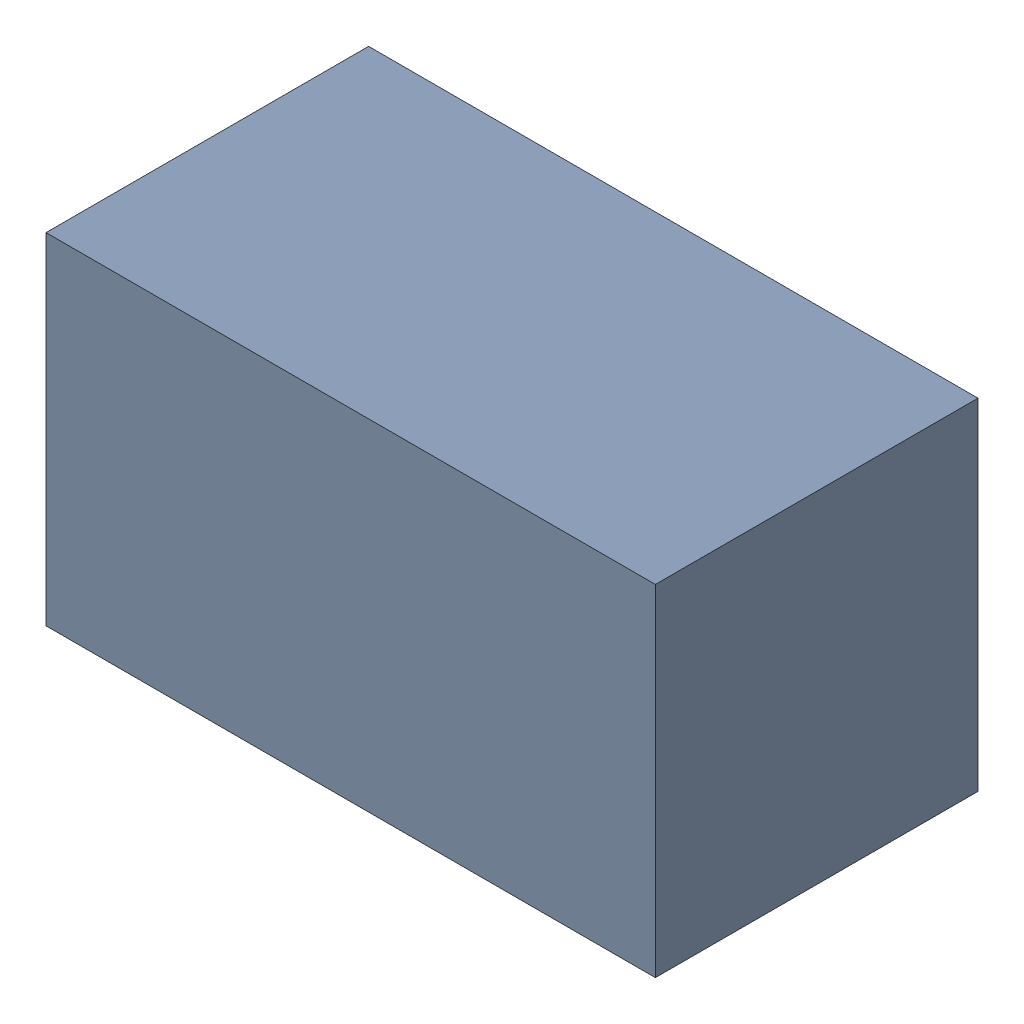
SolidWorks assembly R2, configuration Default. Lengths in mm.
Overall size (1.7 0.95 0.9).
2 component instances, 1 part files, 0 mates.
Components (placement in the parent):
- 580483600-1: 580483600 [Default] at (147.078 284.607 0) size (1.7 0.95 0.9)
  - Extruded_3-1: Extruded_3 [Default] at origin size (1.7 0.95 0.9)
